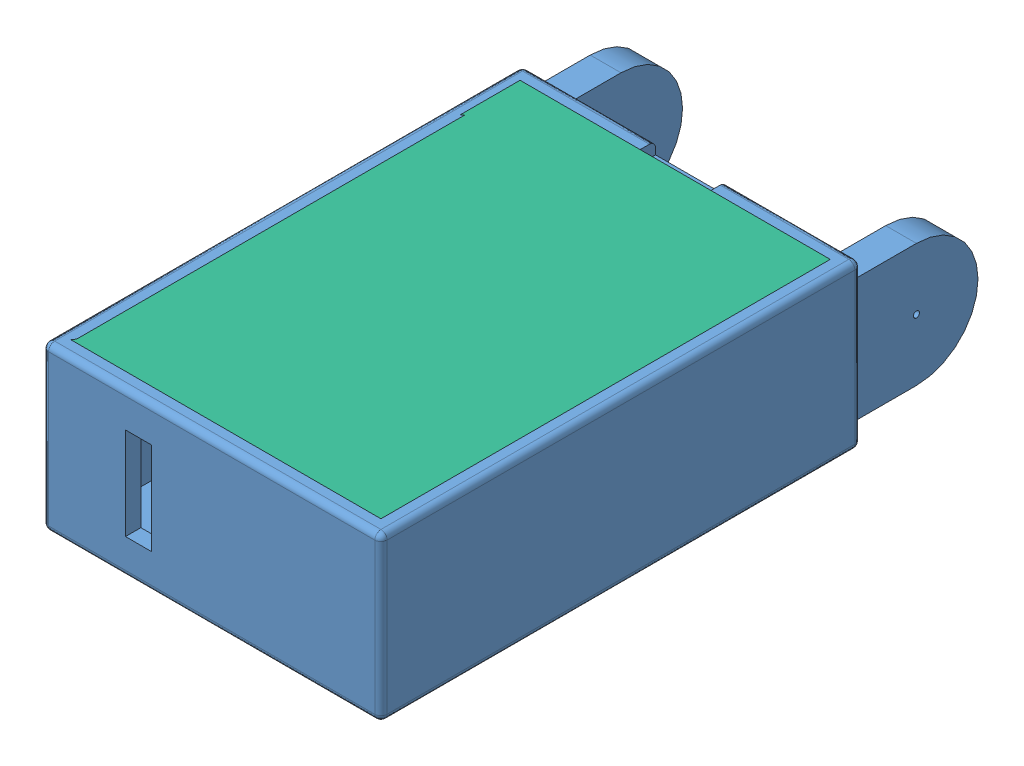
SolidWorks assembly BoxAssembly, configuration Predeterminado. Lengths in mm.
Overall size (55 26.5 98).
6 component instances, 6 part files, 14 mates.
Components (placement in the parent):
- modified servo housing-1: modified servo housing [Predeterminado] at (-2.2195 0.18 147) size (55 26.5 98)
- ArduinoMKR1000 usedforassembly-1: ArduinoMKR1000 usedforassembly [Default] at (-16.2195 -0.07 104.472) x (0 -1 0) z (0 0 1) size (25 21 64.15)
- SG90 BODYusedforassembly-1: SG90 BODYusedforassembly [Default] at (13.7742 0.0284 117.0553) x (0 0 -1) z (0 -1 0) size (32.36 29.6 12.65)
- SG90 ARMusedforassemblye-1: SG90 ARMusedforassemblye [Default] at (20.6703 -6.2708 123.3545) x (0 0.127733 0.991809) z (0 0.991809 -0.127733) size (19.74 4.23 7.24)
- Inner guide of the box-1: Inner guide of the box [Predeterminado] at (9.2805 -7.57 100) x (0.588079 0 -0.808804) z (0.808804 0 0.588079) size (14 10 14)
- BoxCover-2: BoxCover [Predeterminado] at (-2.4195 13.43 108) x (1 0 0) z (0 -1 0) size (50.4 73 1)
Mates (geometry in assembly coordinates):
- Coincidente25: coincident anti-aligned: plane of SG90 BODY-1 through (18.0541 -12.57 117.0553) normal (1 0 0); plane of SG90 ARM-1 through (18.0541 -6.2708 123.3545) normal (-1 0 0)
- Concéntrica3: concentric aligned: cylinder of SG90 BODY-1 through (56.943 -6.2708 123.3545) axis (-1 0 0) radius 2.286; cylinder of SG90 ARM-1 through (20.3909 -6.2708 123.3545) axis (-1 0 0) radius 2.286
- Coincidente26: coincident anti-aligned: plane of modified servo housing-1 through (-2.2195 -12.57 147) normal (0 1 0); plane of SG90 BODY-1 through (13.7742 -12.57 117.0553) normal (0 -1 0)
- Coincidente27: coincident anti-aligned: plane of modified servo housing-1 through (22.7805 -12.57 144.5) normal (0 0 -1); plane of SG90 BODY-1 through (7.0305 -12.57 144.5) normal (0 0 1)
- Coincidente35: coincident anti-aligned: plane of modified servo housing-1 through (7.0305 10.93 144.5) normal (1 0 0); plane of SG90 BODY-1 through (7.0305 -12.57 112.1404) normal (-1 0 0)
- Coincidente36: coincident anti-aligned: plane of modified servo housing-1 through (22.7805 -12.57 71.5) normal (0 0 1); plane of Arduino MKR1000 Part-1 through (-14.2195 -0.07 71.5) normal (0 0 -1)
- Coincidente37: coincident anti-aligned: plane of modified servo housing-1 through (-2.2195 -12.57 147) normal (0 1 0); plane of Arduino MKR1000 Part-1 through (-14.7195 -12.57 135.222) normal (0 -1 0)
- Coincidente39: coincident anti-aligned: plane of modified servo housing-1 through (-27.2195 -12.57 144.5) normal (1 0 0); plane of Arduino MKR1000 Part-1 through (-27.2195 -0.07 104.472) normal (-1 0 0)
- Coincidente40: coincident anti-aligned: plane of modified servo housing-1 through (9.2805 -10.57 100) normal (0 1 0); plane of posibleCilindrodeguiadentrodelacaja-1 through (9.2805 -10.57 100) normal (0 -1 0)
- Concéntrica4: concentric aligned: cylinder of modified servo housing-1 through (9.2805 -10.57 100) axis (0 -1 0) radius 1.5; cylinder of posibleCilindrodeguiadentrodelacaja-1 through (9.2805 -10.57 100) axis (0 -1 0) radius 1.5
- Coincidente53: coincident anti-aligned: plane of modified servo housing-1 through (22.7805 -12.57 71.5) normal (0 0 1); plane of BoxCover-2 through (22.7805 12.43 71.5) normal (0 0 -1)
- Coincidente57: coincident anti-aligned: plane of modified servo housing-1 through (22.7805 -12.57 144.5) normal (-1 0 0); plane of BoxCover-2 through (22.7805 12.43 71.5) normal (1 0 0)
- Coincidente58: coincident anti-aligned: plane of modified servo housing-1 through (22.7805 -12.57 71.5) normal (0 0 1); plane of BoxCover-2 through (22.7805 12.43 71.5) normal (0 0 -1)
- Coincidente60: coincident anti-aligned: line of modified servo housing-1 through (22.7805 13.43 71.5) axis (-1 0 0); line of tapaCaja-2 through (-27.6195 13.43 71.5) axis (1 0 0)
